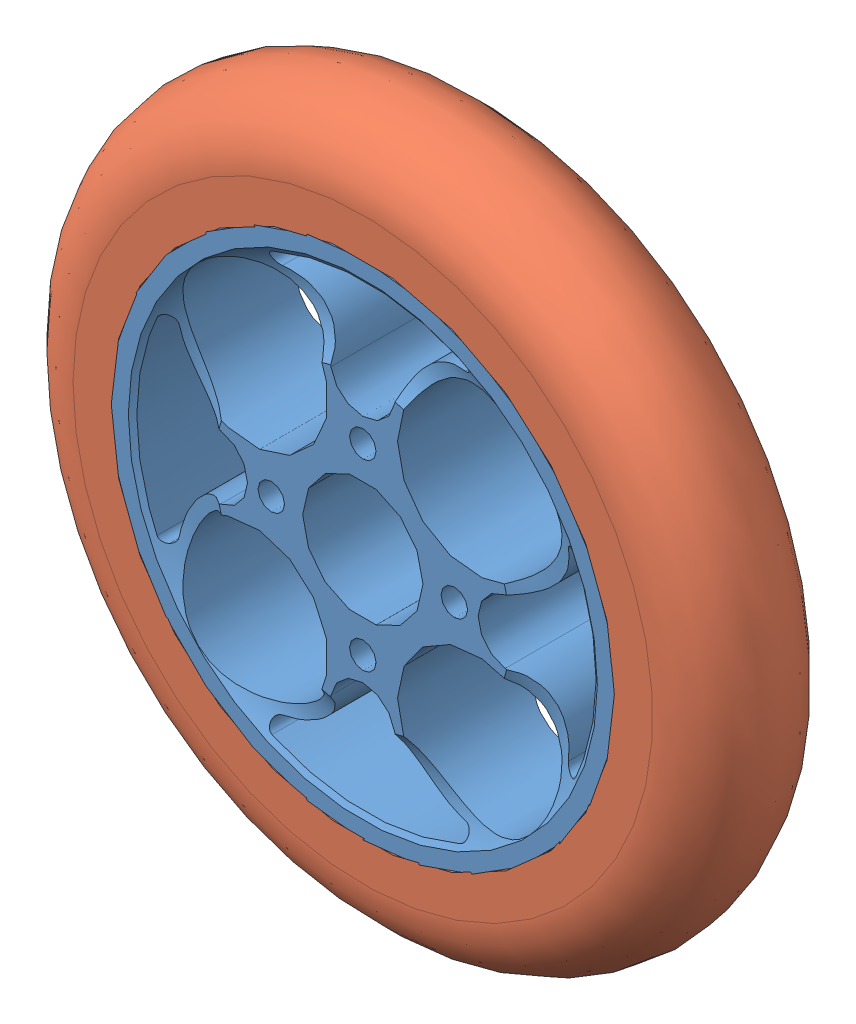
SolidWorks assembly roue, configuration Défaut. Lengths in mm.
Overall size (130 130 25.92).
2 component instances, 2 part files, 4 mates.
Components (placement in the parent):
- moyeu roue-1: moyeu roue [Défaut] at origin size (112 112 25.92)
- galet caoutchouc-1: galet caoutchouc [Défaut] x (0 0 -1) z (1 0 0) size (24 130 130)
Mates (geometry in assembly coordinates):
- Sur place1: in place: plane of galet caoutchouc-1; moOrthogonalPlaneRef_w of galet caoutchouc-1 through (-1000 0 0) axis (0 0 1); line of galet caoutchouc-1 through (0 0 0) axis (0 0 -1); unknown of galet caoutchouc-1
- Coïncidente1: coincident aligned: plane of galet caoutchouc-1; plane of assembly
- Coïncidente2: coincident aligned: plane of galet caoutchouc-1; moOrthogonalPlaneRef_w of assembly
- Coïncidente3: coincident anti-aligned: plane of galet caoutchouc-1; moOrthogonalPlaneRef_w of assembly
